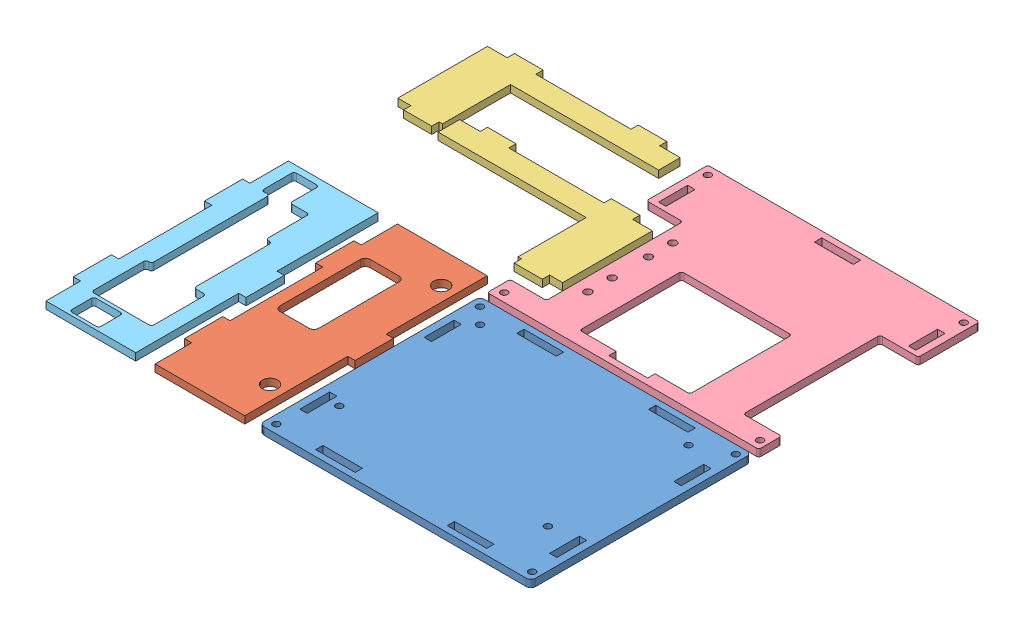
SolidWorks assembly Corte, configuration Predeterminado. Lengths in mm.
Overall size (203 3 185).
6 component instances, 5 part files, 21 mates.
Components (placement in the parent):
- Base-1: Base [Predeterminado] at (-56 0 139.5) size (112 3 91)
- Frontal-1: Frontal [Predeterminado] at (-136.5 3 135) x (0 0 -1) z (0 -1 0) size (100 43 3)
- Lateral-1: Lateral [Predeterminado] at (-160.15 0 21.5) x (-1 0 0) z (0 1 0) size (79.5 43 3)
- Lateral-2: Lateral [Predeterminado] at (-139.75 3 53.4) x (1 0 0) z (0 -1 0) size (79.5 43 3)
- Tapa superior-1: Tapa superior [Predeterminado] at (-56 3 45.5) x (1 0 0) z (0 -1 0) size (112 91 3)
- Trasera-1: Trasera [Predeterminado] at (-181.5 3 135) x (0 0 -1) z (0 -1 0) size (100 43 3)
Mates (geometry in assembly coordinates):
- Coincidente1: coincident anti-aligned: plane of Tapa superior-1 through (-98 0 26.35) normal (0 -1 0)
- Coincidente2: coincident anti-aligned: plane of Frontal-1 through (-136.5 0 135) normal (0 -1 0)
- Coincidente3: coincident anti-aligned: plane of Trasera-1 through (-181.5 0 135) normal (0 -1 0)
- Coincidente5: coincident anti-aligned: plane of Lateral-2 through (-139.75 0 53.4) normal (0 -1 0)
- Coincidente6: coincident anti-aligned: plane of Base-1 through (-2 0 96) normal (0 -1 0)
- Coincidente7: coincident anti-aligned: plane of Lateral-1 through (-160.15 0 21.5) normal (0 -1 0)
- Coincidente8: coincident anti-aligned: plane of Tapa superior-1 through (-111 0 0) normal (0 0 -1)
- Paralelo1: parallel aligned: plane of Lateral-2 through (-139.75 0 31.9) normal (0 0 -1); plane of Tapa superior-1 through (-111 0 0) normal (0 0 -1)
- Paralelo2: parallel aligned: plane of Base-1 through (-110 3 94) normal (0 0 -1); plane of Tapa superior-1 through (-111 0 0) normal (0 0 -1)
- Coincidente12: coincident aligned: plane of Tapa superior-1 through (0 0 24.2) normal (1 0 0)
- Coincidente13: coincident aligned: plane of Base-1 through (0 3 96) normal (1 0 0); plane of Tapa superior-1 through (0 0 90) normal (1 0 0)
- Coincidente14: coincident aligned: plane of Lateral-1 through (-160.15 3 0) normal (0 0 -1); plane of Tapa superior-1 through (-111 0 0) normal (0 0 -1)
- Distancia1: distance = 3 mm anti-aligned: plane of Base-1 through (-110 3 94) normal (0 0 -1); plane of Tapa superior-1 through (-111 0 91) normal (0 0 1)
- Distancia2: distance = 3 mm anti-aligned: plane of Lateral-2 through (-100 0 53.4) normal (1 0 0); plane of Tapa superior-1 through (-97 0 80.6) normal (-1 0 0)
- Distancia3: distance = 20 mm anti-aligned: plane of Lateral-2 through (-139.75 0 31.9) normal (0 0 -1); plane of Lateral-1 through (-160.15 3 11.9) normal (0 0 1)
- Coincidente18: coincident aligned: plane of Base-1 through (-110 3 185) normal (0 0 1); plane of Trasera-1
- Coincidente20: coincident aligned: plane of Base-1 through (-110 3 185) normal (0 0 1); plane of Trasera-1 through (-181.5 0 185) normal (0 0 1)
- Distancia4: distance = 3 mm anti-aligned: plane of Frontal-1 through (-115 0 135) normal (1 0 0); plane of Base-1 through (-112 3 96) normal (-1 0 0)
- Distancia5: distance = 5 mm anti-aligned: plane of Trasera-1 through (-160 0 135) normal (1 0 0); plane of Frontal-1 through (-155 0 135) normal (-1 0 0)
- Coincidente23: coincident aligned: plane of Frontal-1 through (-136.5 0 185) normal (0 0 1); plane of Trasera-1 through (-181.5 0 185) normal (0 0 1)
- Distancia6: distance = 2 mm anti-aligned: plane of Lateral-1 through (-181.5 3 21.5) normal (1 0 0); plane of Lateral-2 through (-179.5 0 53.4) normal (-1 0 0)
